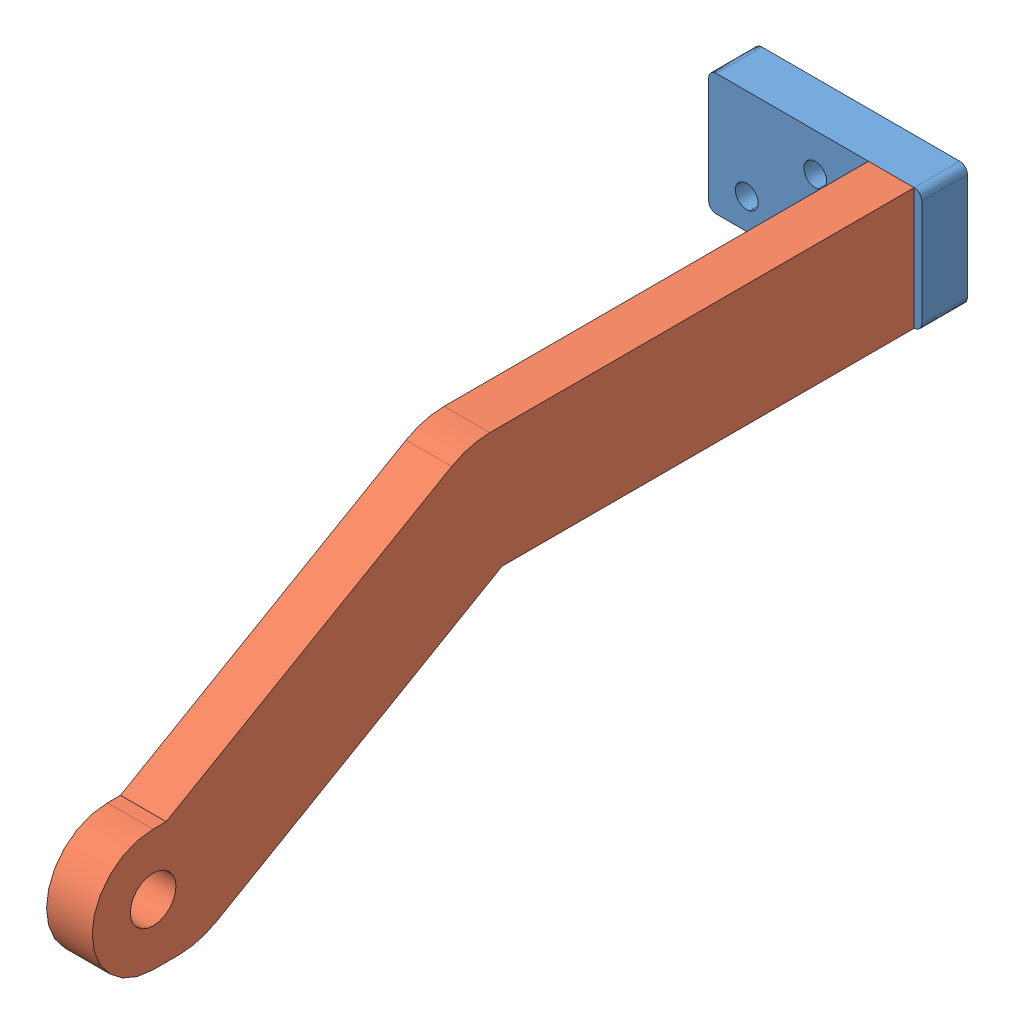
SolidWorks assembly 轴4安装装配体, configuration 默认. Lengths in mm.
Overall size (28 39 113.98).
2 component instances, 2 part files, 4 mates.
Components (placement in the parent):
- 轴4安装片-1: 轴4安装片 [默认] at (-14.6965 -10.8974 23) size (28 16 6)
- 零件2-1: 零件2 [默认] at (-7.6965 -22.0647 79.4913) x (0 1 0) z (1 0 0) size (39 107.98 6)
Mates (geometry in assembly coordinates):
- 重合1: coincident anti-aligned: plane of 轴4安装片-1 through (-14.6965 -10.8974 29) normal (0 0 1); plane of 零件2-1 through (4.123 -61.6077 29) normal (0 0 -1)
- 重合3: coincident aligned: plane of 轴4安装片-1 through (-0.6965 -18.8974 29) normal (0 -1 0); plane of 零件2-1 through (-1.6965 -18.8974 83.1436) normal (0 -1 0)
- 同心1: concentric aligned: cylinder of 轴4安装片-1 through (-4.6965 -7.3974 29.4) axis (0 0 -1) radius 1.5; cylinder of 零件2-1 through (-4.6965 -7.3974 29) axis (0 0 -1) radius 1.25
- 同心2: concentric aligned: cylinder of 轴4安装片-1 through (-4.6965 -14.3974 29.4) axis (0 0 -1) radius 1.5; cylinder of 零件2-1 through (-4.6965 -14.3974 29) axis (0 0 -1) radius 1.25
